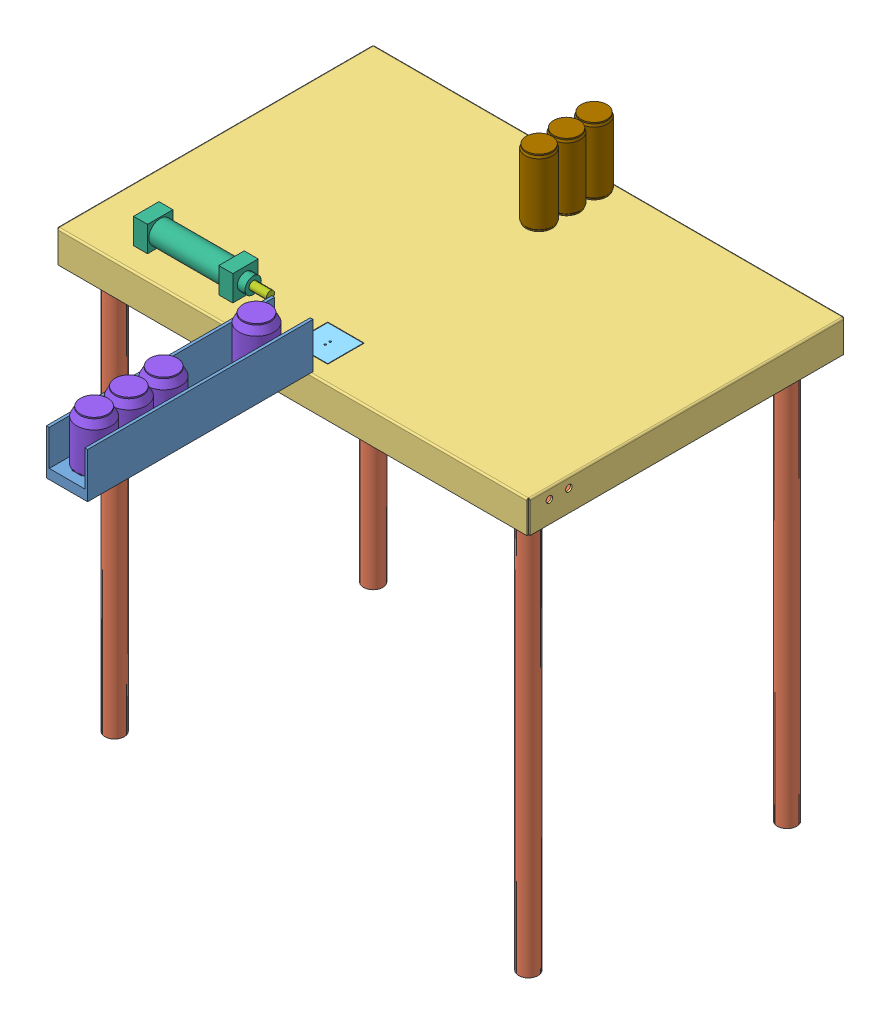
SolidWorks assembly Full_Assembly_v10, configuration Default. Lengths in mm.
Overall size (927.1 1032.54 1072.2).
26 component instances, 14 part files, 85 mates.
Components (placement in the parent):
- Goose Output-1: Goose Output [Default] at (293.9688 417.0931 1038.3317) size (80.96 88.9 442.73)
- M37_Metal_Table_v2-1: M37_Metal_Table_v2 [Default] at (-122.75 348.1575 1031.9817) size (914.4 863.6 609.6)
- Table Topper-1: Table Topper [Default] at (-125.925 348.1575 1035.1567) size (927.1 62.58 622.3)
- Load Cell Assembly-1: Load Cell Assembly [Default] at (309.0555 355.8164 890.1864) size (69.85 23.2 103.99)
  - Load Cell and Brace-1: Load Cell and Brace [Default] at (-9.1055 31.7162 92.7424) size (69 14.2 83)
  - scalePlate_v2_234-1: scalePlate_v2_234 [Default] at (-9.5305 54.9162 113.7283) x (0 0 -1) z (-1 0 0) size (69.85 9 69.85)
- Cylinder-1: Cylinder [Default] at (-22.0508 460.7325 943.9897) x (0 0 1) z (1 0 0) size (50 50 210)
- Rod-1: Rod [Default] at (221.9492 435.7325 968.9897) x (0 0.637822 -0.770184) z (0 0.770184 0.637822) size (16 134 16)
- can355mL-1: can355mL [Default] at (334.45 410.7325 1291.3582) x (0 0 -1) z (1 0 0) size (68.26 122.24 68.26)
- can355mL-2: can355mL [Default] at (334.45 410.7325 1427.8832) x (0 0 -1) z (1 0 0) size (68.26 122.24 68.26)
- can355mL-3: can355mL [Default] at (334.45 410.7325 1359.6207) x (0 0 -1) z (1 0 0) size (68.26 122.24 68.26)
- can250mL-1: can250mL [Default] at (334.45 410.7325 553.8493) x (-0.934308 0 -0.356465) z (0.356465 0 -0.934308) size (53.98 131.76 53.98)
- can250mL-2: can250mL [Default] at (334.45 410.7325 499.8743) x (0.439436 0 -0.898274) z (0.898274 0 0.439436) size (53.98 131.76 53.98)
- can250mL-3: can250mL [Default] at (334.45 410.7325 445.8993) x (0.515444 0 0.856923) z (-0.856923 0 0.515444) size (53.98 131.76 53.98)
- can355mL-7: can355mL [Default] at (334.45 410.7325 1108.8451) x (0 0 -1) z (1 0 0) size (68.26 122.24 68.26)
- AmpCase_Assembly_v1-1: AmpCase_Assembly_v1 [Default] at (358.7361 448.8533 915.6449) x (0 0 -1) z (-1 0 0) size (83 33 59)
  - AmpCase_LID_83x59x33_v1-1: AmpCase_LID_83x59x33_v1 [Default] at (42.2994 74.2958 -6.3457) x (1 0 0) z (0 0 -1) size (83 7 59)
  - AmpCase83x59x33_v1-1: AmpCase83x59x33_v1 [Default] at (42.2994 41.2958 52.6543) size (83 26 59)
- Solenoid_v1-1: Solenoid_v1 [Default] at (427.4711 385.5575 964.0053) size (118 22 83)
- Slats_Long_v1-1: Slats_Long_v1 [Default] at (-125.925 374.5575 890.8298) size (920.75 33 3.17)
- Slats_Long_v1-2: Slats_Long_v1 [Default] at (-125.925 374.5575 774.8933) size (920.75 33 3.17)
- Slats_Short_v1-1: Slats_Short_v1 [Default] at (277.3732 374.5575 419.2067) x (0 0 1) z (-1 0 0) size (615.95 33 3.17)
- Slats_Short_v1-2: Slats_Short_v1 [Default] at (386.797 374.5575 419.2067) x (0 0 1) z (-1 0 0) size (615.95 33 3.17)
- Slats_Short_v1-3: Slats_Short_v1 [Default] at (517.0317 374.5575 419.2067) x (0 0 1) z (-1 0 0) size (615.95 33 3.17)
- Slats_Short_v1-4: Slats_Short_v1 [Default] at (606.9406 374.5575 419.2067) x (0 0 1) z (-1 0 0) size (615.95 33 3.17)
- Slats_Short_v1-5: Slats_Short_v1 [Default] at (700.588 374.5575 419.2067) x (0 0 1) z (-1 0 0) size (615.95 33 3.17)
Mates (geometry in assembly coordinates):
- Width1: width aligned: plane of M37_Metal_Table_v2-1 through (791.65 373.5575 1031.9817) normal (1 0 0); plane of M37_Metal_Table_v2-1 through (-122.75 373.5575 1031.9817) normal (-1 0 0); plane of Table Topper-1 through (798 407.5575 1035.1567) normal (1 0 0); plane of Table Topper-1 through (-129.1 407.5575 1035.1567) normal (-1 0 0)
- Width2: width aligned: plane of M37_Metal_Table_v2-1 through (-122.75 373.5575 1031.9817) normal (0 0 1); plane of M37_Metal_Table_v2-1 through (-122.75 373.5575 422.3817) normal (0 0 -1); plane of Table Topper-1 through (-125.925 407.5575 1038.3317) normal (0 0 1); plane of Table Topper-1 through (-125.925 407.5575 416.0317) normal (0 0 -1)
- Distance1: distance = 863.6 mm aligned: plane of M37 Metal Table-1 through (-122.75 -446.5069 1031.9817) normal (0 -1 0); plane of Goose Output-1 through (374.9313 417.0931 1481.0664) normal (0 -1 0)
- LimitDistance1: limit distance = 423.0687 mm aligned: plane of Goose Output-1 through (374.9313 505.9931 1481.0664) normal (1 0 0); plane of Table Topper-1 through (798 407.5575 1035.1567) normal (1 0 0)
- LimitDistance2: limit distance = 423.0687 mm aligned: plane of Table Topper-1 through (-129.1 407.5575 1035.1567) normal (-1 0 0); plane of Goose Output-1 through (293.9688 417.0931 1481.0664) normal (-1 0 0)
- Parallel1: parallel aligned: plane of Goose Output-1 through (299.525 436.1431 1481.0664) normal (0 1 0); plane of Table Topper-1 through (-125.925 410.7325 1035.1567) normal (0 1 0)
- Coincident7: coincident aligned: plane of Table Topper-1 through (-125.925 410.7325 1035.1567) normal (0 1 0); plane of Load Cell Assembly-1/scalePlate_v2_234-1 through (299.525 410.7325 1003.9147) normal (0 1 0)
- Concentric1: concentric anti-aligned: cylinder of Cylinder-1 through (187.9492 435.7325 968.9897) axis (-1 0 0) radius 16; cylinder of Rod-1 through (87.9492 435.7325 968.9897) axis (1 0 0) radius 8
- LimitDistance3: limit distance = 34 mm aligned: plane of Rod-1 through (221.9492 435.7325 968.9897) normal (1 0 0); plane of Cylinder-1 through (187.9492 435.7325 968.9897) normal (1 0 0)
- Parallel2: parallel anti-aligned: plane of Table Topper-1 through (-125.925 407.5575 1038.3317) normal (0 0 1); plane of Cylinder-1 through (172.9492 460.7325 943.9897) normal (0 0 -1)
- Coincident9: coincident anti-aligned: plane of Table Topper-1 through (-125.925 410.7325 1035.1567) normal (0 1 0); plane of Cylinder-1 through (5.4492 410.7325 943.9897) normal (0 -1 0)
- Width3: width anti-aligned: plane of Goose Output-1 through (374.9313 505.9931 1481.0664) normal (1 0 0); plane of Goose Output-1 through (293.9688 417.0931 1481.0664) normal (-1 0 0); plane of Load Cell Assembly-1/scalePlate_v2_234-1 through (299.525 406.7325 1003.9147) normal (-1 0 0); plane of Load Cell Assembly-1/scalePlate_v2_234-1 through (369.375 406.7325 1003.9147) normal (1 0 0)
- Width4: width anti-aligned: plane of Cylinder-1 through (172.9492 460.7325 943.9897) normal (0 0 -1); plane of Cylinder-1 through (172.9492 460.7325 993.9897) normal (0 0 1); plane of Load Cell Assembly-1/scalePlate_v2_234-1 through (299.525 406.7325 1003.9147) normal (0 0 1); plane of Load Cell Assembly-1/scalePlate_v2_234-1 through (299.525 406.7325 934.0647) normal (0 0 -1)
- Width5: width anti-aligned: plane of Table Topper-1 through (798 407.5575 1035.1567) normal (1 0 0); plane of Table Topper-1 through (-129.1 407.5575 1035.1567) normal (-1 0 0); plane of Load Cell Assembly-1/scalePlate_v2_234-1 through (299.525 406.7325 1003.9147) normal (-1 0 0); plane of Load Cell Assembly-1/scalePlate_v2_234-1 through (369.375 406.7325 1003.9147) normal (1 0 0)
- Coincident11: coincident anti-aligned: plane of Table Topper-1 through (-125.925 410.7325 1035.1567) normal (0 1 0); plane of can250mL-1 through (310.7186 410.7325 544.7951) normal (0 -1 0)
- Coincident18: coincident anti-aligned: plane of Table Topper-1 through (-125.925 410.7325 1035.1567) normal (0 1 0); plane of can355mL-2 through (334.45 410.7325 1400.8957) normal (0 -1 0)
- Coincident19: coincident anti-aligned: plane of Table Topper-1 through (-125.925 410.7325 1035.1567) normal (0 1 0); plane of can355mL-3 through (334.45 410.7325 1332.6332) normal (0 -1 0)
- Tangent5: tangent anti-aligned: cylinder of can355mL-2 through (334.45 410.7325 1427.8832) axis (0 -1 0) radius 34.1313; cylinder of can355mL-3 through (334.45 410.7325 1359.6207) axis (0 -1 0) radius 34.1313
- Width6: width: plane of Goose Output-1 through (299.525 505.9931 1481.0664) normal (1 0 0); plane of Goose Output-1 through (369.375 436.1431 1481.0664) normal (-1 0 0); cylinder of can250mL-1 through (334.45 410.7325 553.8493) axis (0 -1 0) radius 26.9875
- Width8: width: plane of Goose Output-1 through (369.375 436.1431 1481.0664) normal (-1 0 0); plane of Goose Output-1 through (299.525 505.9931 1481.0664) normal (1 0 0); cylinder of can355mL-2 through (334.45 410.7325 1427.8832) axis (0 -1 0) radius 34.1313
- Width10: width: plane of Goose Output-1 through (299.525 505.9931 1481.0664) normal (1 0 0); plane of Goose Output-1 through (369.375 436.1431 1481.0664) normal (-1 0 0); cylinder of can355mL-3 through (334.45 410.7325 1359.6207) axis (0 -1 0) radius 34.1313
- Coincident20: coincident anti-aligned: plane of Table Topper-1 through (-125.925 410.7325 1035.1567) normal (0 1 0); plane of can250mL-2 through (345.6117 410.7325 477.0581) normal (0 -1 0)
- Coincident21: coincident anti-aligned: plane of Table Topper-1 through (-125.925 410.7325 1035.1567) normal (0 1 0); plane of can250mL-3 through (347.5423 410.7325 467.6651) normal (0 -1 0)
- Tangent6: tangent anti-aligned: cylinder of can250mL-1 through (334.45 410.7325 553.8493) axis (0 -1 0) radius 26.9875; cylinder of can250mL-2 through (334.45 410.7325 499.8743) axis (0 -1 0) radius 26.9875
- Tangent7: tangent anti-aligned: cylinder of can250mL-2 through (334.45 410.7325 499.8743) axis (0 -1 0) radius 26.9875; cylinder of can250mL-3 through (334.45 410.7325 445.8993) axis (0 -1 0) radius 26.9875
- Width11: width: plane of Goose Output-1 through (299.525 505.9931 1481.0664) normal (1 0 0); plane of Goose Output-1 through (369.375 436.1431 1481.0664) normal (-1 0 0); cylinder of can250mL-2 through (334.45 410.7325 499.8743) axis (0 -1 0) radius 26.9875
- Width12: width: plane of Goose Output-1 through (299.525 505.9931 1481.0664) normal (1 0 0); plane of Goose Output-1 through (369.375 436.1431 1481.0664) normal (-1 0 0); cylinder of can250mL-3 through (334.45 410.7325 445.8993) axis (0 -1 0) radius 26.9875
- Coincident22: coincident anti-aligned: plane of Goose Output-1 through (293.9688 417.0931 1038.3317) normal (0 0 -1); plane of Table Topper-1 through (-125.925 407.5575 1038.3317) normal (0 0 1)
- Width14: width aligned: plane of Table Topper-1 through (370.391 348.1575 1004.9307) normal (-1 0 0); plane of Load Cell Assembly-1/scalePlate_v2_234-1 through (298.509 348.1575 1004.9307) normal (1 0 0); plane of Table Topper-1 through (299.525 406.7325 1003.9147) normal (-1 0 0); plane of Load Cell Assembly-1/scalePlate_v2_234-1 through (369.375 406.7325 1003.9147) normal (1 0 0)
- Width15: width anti-aligned: plane of Table Topper-1 through (298.509 348.1575 1004.9307) normal (0 0 -1); plane of Load Cell Assembly-1/scalePlate_v2_234-1 through (298.509 348.1575 933.0487) normal (0 0 1); plane of Table Topper-1 through (299.525 406.7325 1003.9147) normal (0 0 1); plane of Load Cell Assembly-1/scalePlate_v2_234-1 through (299.525 406.7325 934.0647) normal (0 0 -1)
- Width17: width: plane of Goose Output-1 through (369.375 436.1431 1481.0664) normal (-1 0 0); plane of can355mL-4 through (299.525 505.9931 1481.0664) normal (1 0 0); cylinder of Goose Output-1 through (334.45 436.1431 1259.8293) axis (0 -1 0) radius 34.1313
- Coincident31: coincident anti-aligned: plane of Table Topper-1 through (-125.925 410.7325 1035.1567) normal (0 1 0); plane of can355mL-7 through (334.45 410.7325 1081.8576) normal (0 -1 0)
- Width19: width: plane of Goose Output-1 through (369.375 436.1431 1481.0664) normal (-1 0 0); plane of can355mL-7 through (299.525 505.9931 1481.0664) normal (1 0 0); cylinder of Goose Output-1 through (334.45 410.7325 1108.8451) axis (0 -1 0) radius 34.1313
- Coincident33: coincident anti-aligned: plane of Table Topper-1 through (-125.925 410.7325 1035.1567) normal (0 1 0); plane of can355mL-1 through (334.45 410.7325 1264.3707) normal (0 -1 0)
- Tangent13: tangent anti-aligned: cylinder of can355mL-1 through (334.45 410.7325 1291.3582) axis (0 -1 0) radius 34.1313; cylinder of can355mL-3 through (334.45 410.7325 1359.6207) axis (0 -1 0) radius 34.1313
- Width20: width: plane of Goose Output-1 through (299.525 505.9931 1481.0664) normal (1 0 0); plane of can355mL-1 through (369.375 436.1431 1481.0664) normal (-1 0 0); cylinder of Goose Output-1 through (334.45 410.7325 1291.3582) axis (0 -1 0) radius 34.1313
- Parallel4: parallel aligned: plane of M37_Metal_Table_v2-1 through (-122.75 373.5575 1031.9817) normal (0 0 1); plane of can355mL-7 through (334.45 410.7325 1142.9764) normal (0 0 1)
- Parallel5: parallel aligned: plane of M37_Metal_Table_v2-1 through (-122.75 373.5575 1031.9817) normal (0 0 1); plane of can355mL-2 through (334.45 410.7325 1462.0144) normal (0 0 1)
- Parallel6: parallel aligned: plane of M37_Metal_Table_v2-1 through (-122.75 373.5575 1031.9817) normal (0 0 1); plane of can355mL-3 through (334.45 410.7325 1393.7519) normal (0 0 1)
- Parallel7: parallel aligned: plane of M37_Metal_Table_v2-1 through (-122.75 373.5575 1031.9817) normal (0 0 1); plane of can355mL-1 through (334.45 410.7325 1325.4894) normal (0 0 1)
- LimitDistance14: limit distance = 182.5131 mm aligned: plane of can355mL-7 through (334.45 410.7325 1142.9764) normal (0 0 1); plane of can355mL-1 through (334.45 410.7325 1325.4894) normal (0 0 1)
- Tangent14: tangent anti-aligned: cylinder of can355mL-9 through (334.45 412.9931 1319.9352) axis (0 -1 0) radius 34.1313; cylinder of can355mL-10 through (334.45 412.9931 1388.1977) axis (0 -1 0) radius 34.1313
- Tangent15: tangent anti-aligned: cylinder of can355mL-8 through (334.45 412.9931 1456.4602) axis (0 -1 0) radius 34.1313; cylinder of can355mL-10 through (334.45 412.9931 1388.1977) axis (0 -1 0) radius 34.1313
- Coincident38: coincident anti-aligned: plane of Table Topper-1 through (-125.925 410.7325 1035.1567) normal (0 1 0); plane of can355mL-8 through (334.45 412.9931 1429.4727) normal (0 -1 0)
- Coincident39: coincident aligned: plane of can355mL-9 through (334.45 412.9931 1292.9477) normal (0 -1 0); plane of can355mL-10 through (334.45 412.9931 1361.2102) normal (0 -1 0)
- Coincident40: coincident anti-aligned: plane of Table Topper-1 through (-125.925 410.7325 1035.1567) normal (0 1 0); plane of can355mL-10 through (334.45 412.9931 1361.2102) normal (0 -1 0)
- Width21: width: plane of Goose Output-1 through (299.525 505.9931 1481.0664) normal (1 0 0); plane of Goose Output-1 through (369.375 436.1431 1481.0664) normal (-1 0 0); cylinder of can355mL-8 through (334.45 412.9931 1456.4602) axis (0 -1 0) radius 34.1313
- Width22: width: plane of Goose Output-1 through (374.9313 505.9931 1481.0664) normal (1 0 0); plane of Goose Output-1 through (293.9688 417.0931 1481.0664) normal (-1 0 0); cylinder of can355mL-10 through (334.45 412.9931 1388.1977) axis (0 -1 0) radius 34.1313
- Width23: width: plane of Goose Output-1 through (374.9313 505.9931 1481.0664) normal (1 0 0); plane of Goose Output-1 through (293.9688 417.0931 1481.0664) normal (-1 0 0); cylinder of can355mL-9 through (334.45 412.9931 1319.9352) axis (0 -1 0) radius 34.1313
- LimitDistance15: limit distance = 98.6078 mm aligned: plane of can355mL-9 through (334.45 412.9931 1354.0664) normal (0 0 1); plane of can355mL-2 through (334.45 410.7325 1462.0144) normal (0 0 1)
- Parallel8: parallel aligned: plane of M37_Metal_Table_v2-1 through (-122.75 373.5575 1031.9817) normal (0 0 1); plane of can355mL-8 through (334.45 412.9931 1490.5914) normal (0 0 1)
- Parallel10: parallel aligned: plane of M37_Metal_Table_v2-1 through (-122.75 373.5575 1031.9817) normal (0 0 1); plane of can355mL-10 through (334.45 412.9931 1422.3289) normal (0 0 1)
- LimitDistance16: limit distance = 0 mm aligned: plane of can355mL-8 through (334.45 412.9931 1490.5914) normal (0 0 1); plane of Goose Output-1 through (293.9688 417.0931 1481.0664) normal (0 0 1)
- Parallel12: parallel aligned: plane of M37_Metal_Table_v2-1 through (-122.75 373.5575 1031.9817) normal (0 0 1); plane of can355mL-11 through (334.45 412.9931 1012.7539) normal (0 0 1)
- LimitDistance18: limit distance = 68.2625 mm aligned: plane of can355mL-11 through (334.45 412.9931 1012.7539) normal (0 0 1); plane of can355mL-7 through (334.45 410.7325 1142.9764) normal (0 0 1)
- PathMate3: path: point of can355mL-11
- Parallel13: parallel anti-aligned: plane of Table Topper-1 through (-125.925 410.7325 1035.1567) normal (0 1 0); plane of can355mL-11 through (334.45 412.9931 951.6352) normal (0 -1 0)
- Parallel14: parallel aligned: plane of M37_Metal_Table_v2-1 through (-122.75 373.5575 1031.9817) normal (0 0 1); plane of can355mL-11 through (334.45 412.9931 1012.7539) normal (0 0 1)
- Coincident41: coincident aligned: plane of M37_Metal_Table_v2-1 through (-122.75 348.1575 1031.9817) normal (0 -1 0); plane of Table Topper-1 through (-125.925 348.1575 1035.1567) normal (0 -1 0)
- Coincident42: coincident anti-aligned: plane of Table Topper-1 through (-125.925 407.5575 1035.1567) normal (0 -1 0); plane of AmpCase_Assembly_v1-1/AmpCase83x59x33_v1-1 through (306.0817 407.5575 873.3456) normal (0 1 0)
- Parallel15: parallel aligned: plane of M37_Metal_Table_v2-1 through (-122.75 373.5575 1031.9817) normal (0 0 1); plane of AmpCase_Assembly_v1-1/AmpCase83x59x33_v1-1 through (306.0817 404.5575 873.3456) normal (0 0 1)
- Parallel16: parallel aligned: plane of M37_Metal_Table_v2-1 through (-122.75 373.5575 1031.9817) normal (0 0 1); plane of Solenoid_v1-1 through (427.4711 407.5575 964.0053) normal (0 0 1)
- Coincident45: coincident aligned: plane of AmpCase_Assembly_v1-1/AmpCase83x59x33_v1-1 through (306.0817 407.5575 873.3456) normal (0 1 0); plane of Solenoid_v1-1 through (427.4711 407.5575 964.0053) normal (0 1 0)
- Coincident46: coincident aligned: plane of M37_Metal_Table_v2-1 through (-122.75 348.1575 1031.9817) normal (0 -1 0); plane of M37 Metal Table-2 through (-136.9971 348.1681 1554.8123) normal (0 -1 0)
- Parallel17: parallel aligned: plane of M37_Metal_Table_v2-1 through (-122.75 373.5575 1031.9817) normal (0 0 1); plane of Slats_Long_v1-1 through (-125.925 374.5575 894.0048) normal (0 0 1)
- Parallel18: parallel anti-aligned: plane of M37_Metal_Table_v2-1 through (791.65 373.5575 1031.9817) normal (1 0 0); plane of Slats_Short_v1-1 through (274.1982 374.5575 419.2067) normal (-1 0 0)
- Coincident48: coincident aligned: plane of AmpCase_Assembly_v1-1/AmpCase83x59x33_v1-1 through (306.0817 407.5575 873.3456) normal (0 1 0); plane of Slats_Long_v1-1 through (-125.925 407.5575 894.0048) normal (0 1 0)
- Coincident49: coincident aligned: plane of AmpCase_Assembly_v1-1/AmpCase83x59x33_v1-1 through (306.0817 407.5575 873.3456) normal (0 1 0); plane of Slats_Short_v1-1 through (274.1982 407.5575 419.2067) normal (0 1 0)
- Coincident50: coincident anti-aligned: plane of Table Topper-1 through (794.825 407.5575 1035.1567) normal (-1 0 0); plane of Slats_Long_v1-1 through (794.825 374.5575 894.0048) normal (1 0 0)
- Coincident51: coincident anti-aligned: plane of Table Topper-1 through (-125.925 407.5575 1035.1567) normal (0 0 -1); plane of Slats_Short_v1-1 through (274.1982 374.5575 1035.1567) normal (0 0 1)
- Parallel19: parallel aligned: plane of M37_Metal_Table_v2-1 through (791.65 373.5575 1031.9817) normal (1 0 0); plane of Slats_Short_v1-2 through (386.797 374.5575 419.2067) normal (1 0 0)
- Parallel20: parallel aligned: plane of M37_Metal_Table_v2-1 through (791.65 373.5575 1031.9817) normal (1 0 0); plane of Slats_Short_v1-3 through (517.0317 374.5575 419.2067) normal (1 0 0)
- Parallel21: parallel aligned: plane of M37_Metal_Table_v2-1 through (791.65 373.5575 1031.9817) normal (1 0 0); plane of Slats_Short_v1-4 through (606.9406 374.5575 419.2067) normal (1 0 0)
- Coincident52: coincident aligned: plane of AmpCase_Assembly_v1-1/AmpCase83x59x33_v1-1 through (306.0817 407.5575 873.3456) normal (0 1 0); plane of Slats_Short_v1-2 through (383.622 407.5575 419.2067) normal (0 1 0)
- Coincident53: coincident aligned: plane of AmpCase_Assembly_v1-1/AmpCase83x59x33_v1-1 through (306.0817 407.5575 873.3456) normal (0 1 0); plane of Slats_Short_v1-3 through (513.8567 407.5575 419.2067) normal (0 1 0)
- Coincident54: coincident aligned: plane of AmpCase_Assembly_v1-1/AmpCase83x59x33_v1-1 through (306.0817 407.5575 873.3456) normal (0 1 0); plane of Slats_Short_v1-4 through (603.7656 407.5575 419.2067) normal (0 1 0)
- Coincident55: coincident anti-aligned: plane of Table Topper-1 through (-125.925 407.5575 1035.1567) normal (0 0 -1); plane of Slats_Short_v1-2 through (383.622 374.5575 1035.1567) normal (0 0 1)
- Coincident56: coincident anti-aligned: plane of Table Topper-1 through (-125.925 407.5575 1035.1567) normal (0 0 -1); plane of Slats_Short_v1-3 through (513.8567 374.5575 1035.1567) normal (0 0 1)
- Coincident57: coincident anti-aligned: plane of Table Topper-1 through (-125.925 407.5575 1035.1567) normal (0 0 -1); plane of Slats_Short_v1-4 through (603.7656 374.5575 1035.1567) normal (0 0 1)
- Parallel22: parallel aligned: plane of M37_Metal_Table_v2-1 through (791.65 373.5575 1031.9817) normal (1 0 0); plane of Slats_Short_v1-5 through (700.588 374.5575 419.2067) normal (1 0 0)
- Coincident58: coincident anti-aligned: plane of Table Topper-1 through (-125.925 407.5575 1035.1567) normal (0 0 -1); plane of Slats_Short_v1-5 through (697.413 374.5575 1035.1567) normal (0 0 1)
- Coincident59: coincident aligned: plane of AmpCase_Assembly_v1-1/AmpCase83x59x33_v1-1 through (306.0817 407.5575 873.3456) normal (0 1 0); plane of Slats_Short_v1-5 through (697.413 407.5575 419.2067) normal (0 1 0)
- Parallel23: parallel aligned: plane of M37_Metal_Table_v2-1 through (-122.75 373.5575 1031.9817) normal (0 0 1); plane of Slats_Long_v1-2 through (-125.925 374.5575 778.0683) normal (0 0 1)
- Coincident61: coincident anti-aligned: plane of Table Topper-1 through (794.825 407.5575 1035.1567) normal (-1 0 0); plane of Slats_Long_v1-2 through (794.825 374.5575 778.0683) normal (1 0 0)
- Coincident62: coincident aligned: plane of AmpCase_Assembly_v1-1/AmpCase83x59x33_v1-1 through (306.0817 407.5575 873.3456) normal (0 1 0); plane of Slats_Long_v1-2 through (-125.925 407.5575 778.0683) normal (0 1 0)
